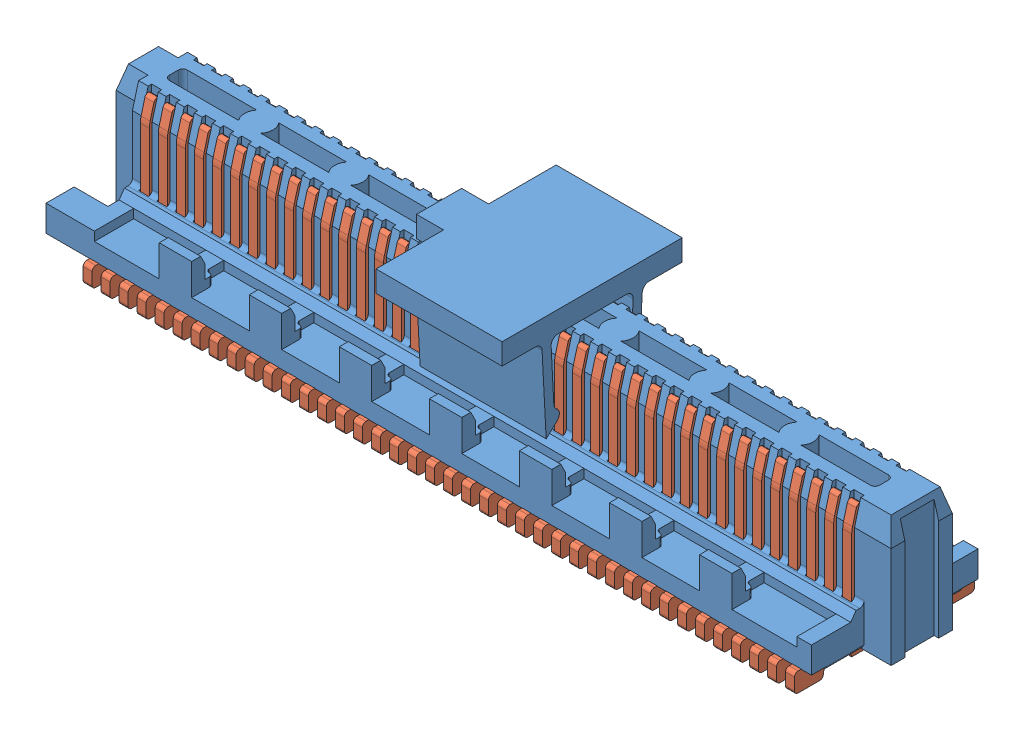
SolidWorks assembly ST4-40-1.00-L-D-P-TR, configuration Default. Lengths in mm.
Overall size (17.6 3.55 4).
3 component instances, 2 part files, 0 mates.
Components (placement in the parent):
- ST4-40-1.00-L-D-P-TR.step-1: ST4-40-1.00-L-D-P-TR.step [Default] at origin size (17.6 3.55 4)
  - ST4-40-1.00-L-D-P-TR_terminal.step-1: ST4-40-1.00-L-D-P-TR_terminal.step [Default] at origin size (17.6 3.23 4)
  - ST4-40-1.00-L-D_pin.step-1: ST4-40-1.00-L-D_pin.step [Default] at (0 -0.32 0) size (15.8 2.97 4)
